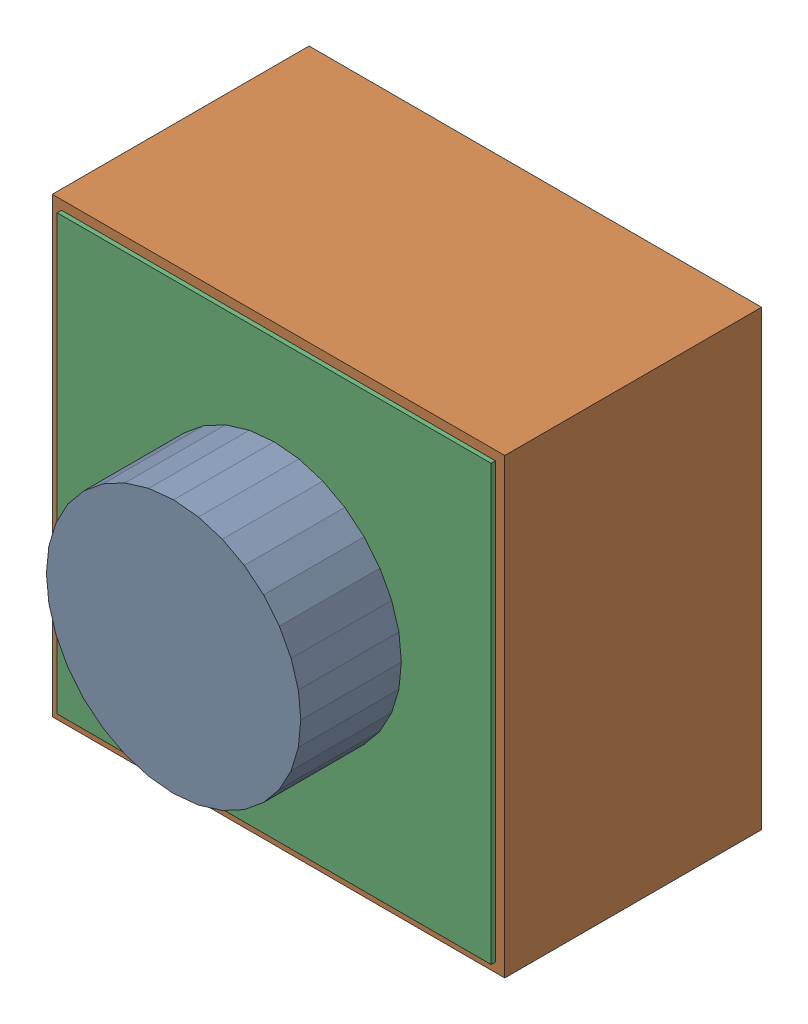
SolidWorks assembly Reset, configuration Default. Lengths in mm.
Overall size (6.25 6.25 5).
6 component instances, 3 part files, 0 mates.
Components (placement in the parent):
- 402661520-1: 402661520 [Default] at (8.9154 107.4674 0) size (3.52 3.52 5)
  - Extruded_22-1: Extruded_22 [Default] at origin size (3.52 3.52 5)
- 402658448-1: 402658448 [Default] at (8.9154 107.4674 0) size (6.25 6.25 3.55)
  - Extruded_23-1: Extruded_23 [Default] at origin size (6.25 6.25 3.55)
- 402657040-1: 402657040 [Default] at (8.9154 107.4674 0) size (6 6 3.61)
  - Extruded_24-1: Extruded_24 [Default] at origin size (6 6 3.61)
